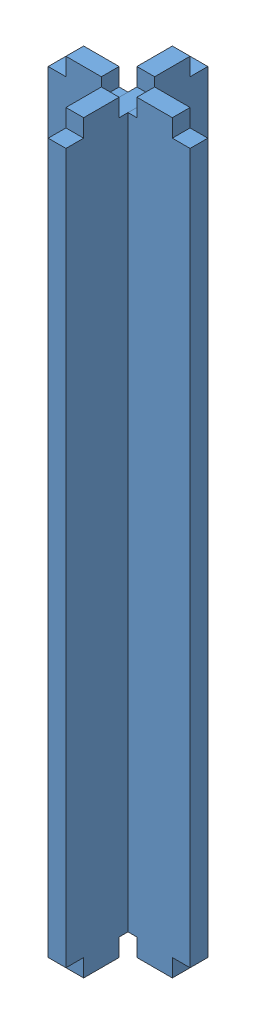
SolidWorks assembly Pata, configuration Predeterminado. Lengths in mm.
Overall size (40 206 40).
2 component instances, 1 part files, 3 mates.
Components (placement in the parent):
- Pata-1: Pata [conf2] at (2.6829 -78.0313 0) size (3 206 40)
- Pata-2: Pata [conf1] at (2.6829 -78.0313 0) x (0 0 -1) z (1 0 0) size (3 206 40)
Mates (geometry in assembly coordinates):
- Coincidente1: coincident anti-aligned: plane of Pata-1 through (4.1829 -78.0313 0) normal (1 0 0); plane of Pata-2 through (4.1829 121.9687 1.501) normal (-1 0 0)
- Coincidente2: coincident anti-aligned: plane of Pata-1 through (1.1819 21.9687 1.5) normal (0 -1 0); plane of Pata-2 through (4.1829 21.9687 1.501) normal (0 1 0)
- Coincidente3: coincident: line of Pata-1 through (4.1829 -78.0313 -1.5) axis (0 1 0); plane of Pata-2 through (2.6829 -78.0313 -1.5) normal (0 0 -1)
